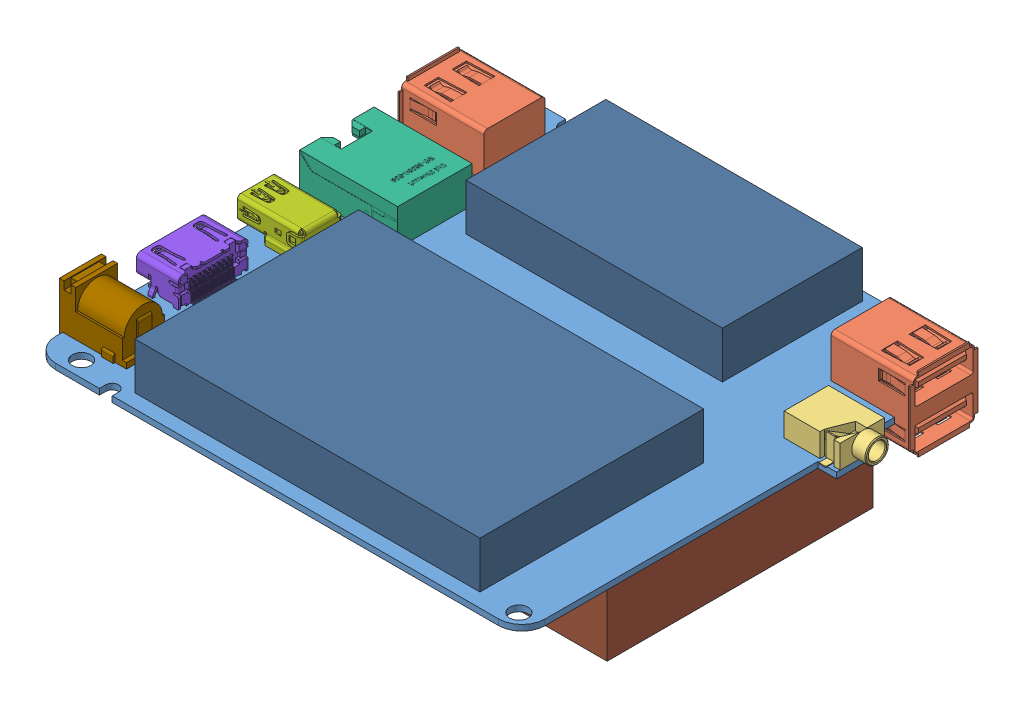
SolidWorks assembly computer, configuration Default. Lengths in mm.
Overall size (112.78 24.5 100).
13 component instances, 11 part files, 26 mates.
Components (placement in the parent):
- computer-pcb-1: computer-pcb [Default] at origin size (109 1.25 100)
- usb-a-double-1: usb-a-double [Default] at (47.745 -3.9 -36.45) x (0 0 -1) z (1 0 0) size (14.6 16.2 17.65)
- audio-jack-1: audio-jack [Défaut] at (56.5 1.25 -19.25) x (-1 0 0) z (0 0 -1) size (15 6 12)
  - mj1-3510-smt_01-1: mj1-3510-smt_01 [Défaut] at origin size (15 6 10.5)
  - mj1-3510-smt_02-1: mj1-3510-smt_02 [Défaut] at origin size (1 0.25 2.25)
  - mj1-3510-smt_03-1: mj1-3510-smt_03 [Défaut] at origin size (1.5 0.25 2.25)
- usb-a-double-2: usb-a-double [Default] at (-44.375 -3.9 -36.45) x (0 0 1) z (-1 0 0) size (14.6 16.2 17.65)
- ethernet-jack-1: ethernet-jack [Default] at (-45.057 -4.375 -15.993) x (0 0 1) z (-1 0 0) size (15.99 16.55 21.05)
- mini-display-port-1: mini-display-port [Default] at (-52.62 -3.25 -3.4195) x (0 0 1) z (-1 0 0) size (9.11 10.68 14.44)
- hdmi-1: hdmi [Default] at (-44.9 4.575 19.5) x (0 0 1) z (-1 0 0) size (16.2 8 9.9)
- power-jack-1: power-jack [Default] at (-45.5 -0.05 39) x (0 0 -1) z (1 0 0) size (9.4 14.5 14.4)
- computer-top-components-1: computer-top-components [Default] at (3.5 1.25 -0.5) size (74 10 95)
- computer-bottom-components-1: computer-bottom-components [Default] at (0 -13.25 3.227) x (0 0 1) z (-1 0 0) size (57 13.25 105)
Mates (geometry in assembly coordinates):
- Distance1: distance = 4.07 mm aligned: plane of usb-a-double-1 through (56.57 10.45 -29.9) normal (1 0 0); plane of computer-pcb-1 through (52.5 1.25 0) normal (1 0 0)
- Distance2: distance = 9.2 mm aligned: plane of usb-a-double-1 through (56.57 10.45 -29.9) normal (0 1 0); plane of computer-pcb-1 through (0 1.25 0) normal (0 1 0)
- Distance3: distance = 7 mm aligned: plane of usb-a-double-1 through (38.92 10.45 -43) normal (0 0 -1); plane of computer-pcb-1 through (0 1.25 -50) normal (0 0 -1)
- Coincident4: coincident aligned: plane of computer-pcb-1 through (56.5 1.25 0) normal (1 0 0); plane of audio-jack-1/mj1-3510-smt_01-1 through (56.5 6.25 -23.75) normal (1 0 0)
- Coincident5: coincident anti-aligned: plane of computer-pcb-1 through (0 1.25 0) normal (0 1 0); plane of audio-jack-1/mj1-3510-smt_01-1 through (56.5 1.25 -23.75) normal (0 -1 0)
- Width1: width anti-aligned: plane of computer-pcb-1 through (0 1.25 -13.5) normal (0 0 1); plane of computer-pcb-1 through (0 1.25 -24.5) normal (0 0 -1); plane of audio-jack-1/mj1-3510-smt_01-1 through (44.5 1.25 -23.75) normal (0 0 -1); plane of audio-jack-1/mj1-3510-smt_01-1 through (44.5 1.25 -14.25) normal (0 0 1)
- Distance5: distance = 0.7 mm aligned: plane of usb-a-double-2 through (-53.2 10.45 -43) normal (-1 0 0); plane of computer-pcb-1 through (-52.5 1.25 0) normal (-1 0 0)
- Coincident8: coincident aligned: plane of usb-a-double-1 through (56.57 10.45 -29.9) normal (0 1 0); plane of usb-a-double-2 through (-53.2 10.45 -43) normal (0 1 0)
- Coincident9: coincident aligned: plane of usb-a-double-1 through (38.92 10.45 -43) normal (0 0 -1); plane of usb-a-double-2 through (-35.55 10.45 -43) normal (0 0 -1)
- Coincident10: coincident aligned: plane of usb-a-double-2 through (-53.2 10.45 -43) normal (-1 0 0); plane of ethernet-jack-1 through (-53.2 9 -23.986) normal (-1 0 0)
- Distance6: distance = 7.75 mm aligned: plane of ethernet-jack-1 through (-32.154 9 -8) normal (0 1 0); plane of computer-pcb-1 through (0 1.25 0) normal (0 1 0)
- Distance7: distance = 42 mm anti-aligned: plane of ethernet-jack-1 through (-53.2 9 -8) normal (0 0 1); plane of computer-pcb-1 through (0 1.25 -50) normal (0 0 -1)
- Coincident12: coincident aligned: plane of usb-a-double-2 through (-53.2 10.45 -43) normal (-1 0 0); plane of mini-display-port-1 through (-53.2 -3.25 -3.4195) normal (-1 0 0)
- Distance8: distance = 0.6 mm anti-aligned: plane of mini-display-port-1 through (-50.0427 1.85 1.741) normal (0 -1 0); plane of computer-pcb-1 through (0 1.25 0) normal (0 1 0)
- Distance9: distance = 55.3 mm anti-aligned: plane of mini-display-port-1 through (-46.535 4.85 5.3) normal (0 0 1); plane of computer-pcb-1 through (0 1.25 -50) normal (0 0 -1)
- Coincident15: coincident anti-aligned: plane of computer-pcb-1 through (0 1.25 0) normal (0 1 0); plane of hdmi-1 through (-48.794 1.25 12.844) normal (0 -1 0)
- Coincident16: coincident aligned: plane of usb-a-double-2 through (-53.2 10.45 -43) normal (-1 0 0); plane of hdmi-1 through (-53.2 6.3959 27.0459) normal (-1 0 0)
- Distance10: distance = 38 mm anti-aligned: plane of hdmi-1 through (-44.02 -0.28 12) normal (0 0 -1); plane of computer-pcb-1 through (0 1.25 50) normal (0 0 1)
- Distance14: distance = 1.3 mm anti-aligned: plane of computer-pcb-1 through (0 1.25 0) normal (0 1 0); plane of power-jack-1 through (-38.8 -0.05 34.5) normal (0 -1 0)
- Coincident19: coincident aligned: plane of usb-a-double-2 through (-53.2 10.45 -43) normal (-1 0 0); plane of power-jack-1 through (-53.2 -0.05 34.5) normal (-1 0 0)
- Distance11: distance = 6.5 mm aligned: plane of power-jack-1 through (-45.5 -0.05 43.5) normal (0 0 1); plane of computer-pcb-1 through (0 1.25 50) normal (0 0 1)
- Coincident21: coincident anti-aligned: plane of computer-pcb-1 through (0 1.25 0) normal (0 1 0); plane of computer-top-components-1 through (3.5 1.25 -0.5) normal (0 -1 0)
- Distance12: distance = 3 mm aligned: plane of computer-top-components-1 through (3.5 11.25 47) normal (0 0 1); plane of computer-pcb-1 through (0 1.25 50) normal (0 0 1)
- Distance13: distance = 12 mm aligned: plane of computer-top-components-1 through (40.5 11.25 -0.5) normal (1 0 0); plane of computer-pcb-1 through (52.5 1.25 0) normal (1 0 0)
- Coincident24: coincident anti-aligned: plane of computer-pcb-1 through (0 0 0) normal (0 -1 0); plane of computer-bottom-components-1 through (0 0 3.227) normal (0 1 0)
- Coincident26: coincident aligned: plane of computer-pcb-1 through (-52.5 1.25 0) normal (-1 0 0); plane of computer-bottom-components-1 through (-52.5 0 -25.273) normal (-1 0 0)
